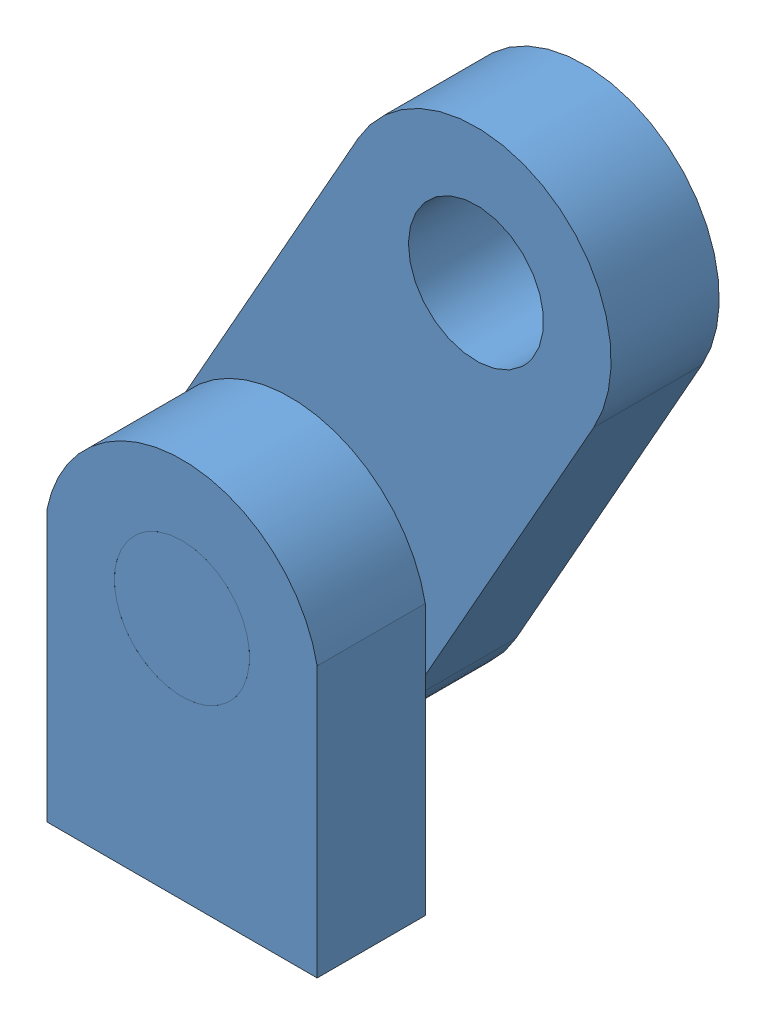
SolidWorks assembly Ensamblaje1, configuration Predeterminado. Lengths in mm.
Overall size (125.5 141.31 40).
3 component instances, 1 part files, 5 mates.
Components (placement in the parent):
- BASE-1: BASE [unión] at (-70.7007 45.0815 29.7098) x (1 0 0) z (0 -1 0) size (25 35 25)
- BASE-2: BASE [Predeterminado] at (-70.2215 25 44.7098) x (1 0 0) z (0 -1 0) size (50 20 70.56)
- BASE-3: BASE [brazo] at (-36.3204 106.0569 44.7098) x (-0.650753 -0.75929 0) z (0.75929 -0.650753 0) size (118.67 20 63.58)
Mates (geometry in assembly coordinates):
- Coincidente1: coincident anti-aligned: plane of BASE-2 through (-45.7007 0 64.7098) normal (0 -1 0); plane of assembly through (0 0 0) normal (0 1 0)
- Concéntrica1: concentric aligned: circle of BASE-1; circle of BASE-2
- Coincidente7: coincident aligned: plane of BASE-1 through (-70.7007 45.0815 64.7098) normal (0 0 1); plane of BASE-2 through (-70.7007 45.0815 64.7098) normal (0 0 1)
- Concéntrica2: concentric anti-aligned: circle of BASE-1; circle of BASE-3
- Coincidente9: coincident anti-aligned: plane of BASE-2 through (-70.7007 45.0815 44.7098) normal (0 0 -1); plane of BASE-3 through (-36.3204 106.0569 44.7098) normal (0 0 1)
